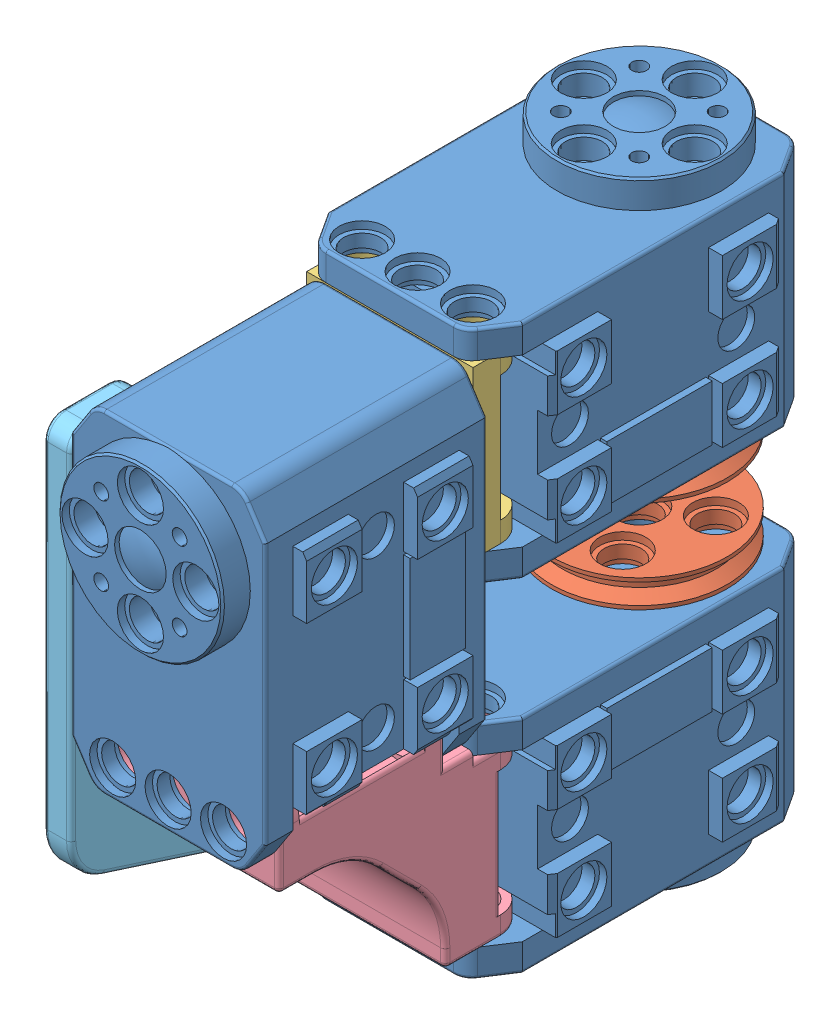
SolidWorks assembly pelvis, configuration correction_jeu. Lengths in mm.
Overall size (28.13 67 67.13).
11 component instances, 5 part files, 13 mates.
Components (placement in the parent):
- XL-320-1: XL-320 [Default] at (-0.6917 36.2165 27.8659)
- assem_motor-1: assem_motor [Default] at (-0.6013 -16.113 33.5308) x (0 1 0) z (-0.707107 0 -0.707107) size (67 46.95 46.95)
  - XL-320_assem-1: XL-320_assem [Default] at (12.4813 24.5225 -2.9973) x (0 -0.707107 0.707107) z (-1 0 0) size (26.26 40.13 30)
    - XL-320-1: XL-320 [Default] at (19.5498 29.4443 -2.8482)
    - SP0-1: SP0 [Default] at (19.5498 29.4443 -16.3482) x (0.541894 0.840447 0) z (-0.840447 0.541894 0) size (19 3 19)
  - XL-320_assem-2: XL-320_assem [Default] at (55.1778 -3.1251 24.6503) x (0 0.707107 -0.707107) z (1 0 0) size (26.26 40.13 30)
    - XL-320-1: XL-320 [Default] at (19.5498 29.4443 -2.8482)
    - SP0-1: SP0 [Default] at (19.5498 29.4443 -16.3482) x (0.541894 0.840447 0) z (-0.840447 0.541894 0) size (19 3 19)
- SPU-5-5: SPU-5 [Default] at (-0.6917 36.2165 12.8659)
- dos-1: dos [Default] at origin
- Part1^pelvis-1: Part1^pelvis [Default] at (-12.6917 36.2165 27.8659) x (0 0 1) z (-1 0 0) size (54.5 51 3) (virtual)
Mates (geometry in assembly coordinates):
- Coincident21: coincident anti-aligned: plane of XL-320-1 through (-0.6917 36.2165 15.8659) normal (0 0 -1); plane of assem_motor-1/XL-320_assem-2/XL-320-1 through (-8.6917 24.2165 15.8659) normal (0 0 1)
- Coincident22: coincident aligned: plane of XL-320-1 through (-12.6917 39.0571 15.8659) normal (-1 0 0); plane of assem_motor-1/XL-320_assem-2/XL-320-1 through (-12.6917 24.2165 -13.9747) normal (-1 0 0)
- Concentric12: concentric anti-aligned: cylinder of assem_motor-1/XL-320_assem-2/XL-320-1 through (5.3083 48.2165 12.8659) axis (0 1 0) radius 2; cylinder of SPU-5-5 through (5.3083 27.2165 12.8659) axis (0 -1 0) radius 2
- Concentric13: concentric anti-aligned: cylinder of assem_motor-1/XL-320_assem-2/XL-320-1 through (-6.6917 48.2165 12.8659) axis (0 1 0) radius 2; cylinder of SPU-5-5 through (-6.6917 27.2165 12.8659) axis (0 -1 0) radius 2
- Coincident42: coincident anti-aligned: plane of assem_motor-1/XL-320_assem-2/XL-320-1 through (-0.6917 27.2165 -11.1341) normal (0 1 0); plane of SPU-5-5 through (-0.6917 27.2165 15.8659) normal (0 -1 0)
- Concentric15: concentric anti-aligned: cylinder of XL-320-1 through (-0.6917 36.2165 15.8659) axis (0 0 -1) radius 2; cylinder of SPU-5-5 through (-0.6917 36.2165 15.8659) axis (0 0 1) radius 2
- Coincident43: coincident anti-aligned: plane of assem_motor-1/XL-320_assem-1/XL-320-1 through (-0.6917 -9.7835 -11.1341) normal (0 1 0); plane of dos-1 through (-0.6917 -9.7835 15.8659) normal (0 -1 0)
- Concentric16: concentric aligned: cylinder of assem_motor-1/XL-320_assem-1/XL-320-1 through (-6.6917 -12.7835 12.8659) axis (0 -1 0) radius 2; cylinder of dos-1 through (-6.6917 15.2165 12.8659) axis (0 -1 0) radius 2.15
- Concentric17: concentric aligned: cylinder of XL-320-1 through (5.3083 12.2165 39.8659) axis (0 0 1) radius 2; cylinder of dos-1 through (5.3083 12.2165 9.8659) axis (0 0 1) radius 2.15
- InPlace4: in place: plane of XL-320-1 through (-12.6917 39.0571 15.8659) normal (-1 0 0); plane of ? through (-12.6917 0 0) normal (-1 0 0); moOrthogonalPlaneRef_w of XL-320-1 through (-12.6917 39.0571 15.8659) normal (-1 0 0); line of ? through (-55 -12.6917 0) axis (0 0 1); plane of XL-320-1 through (-12.6917 39.0571 15.8659) normal (-1 0 0); plane of ? through (-12.6917 0 0) normal (0 0 1); plane of XL-320-1 through (-12.6917 39.0571 15.8659) normal (-1 0 0); unknown of Part1^pelvis-1
- Coincident44: coincident: plane of XL-320-1; plane of Part1^pelvis-1
- Coincident45: coincident: moOrthogonalPlaneRef_w of XL-320-1 through (-12.6917 36.2165 27.8659) normal (0 1 0); plane of Part1^pelvis-1
- Coincident46: coincident: moOrthogonalPlaneRef_w of XL-320-1 through (-12.6917 36.2165 27.8659) normal (0 0 -1); plane of Part1^pelvis-1 through (-12.6917 36.2165 27.8659) normal (0 0 1)
